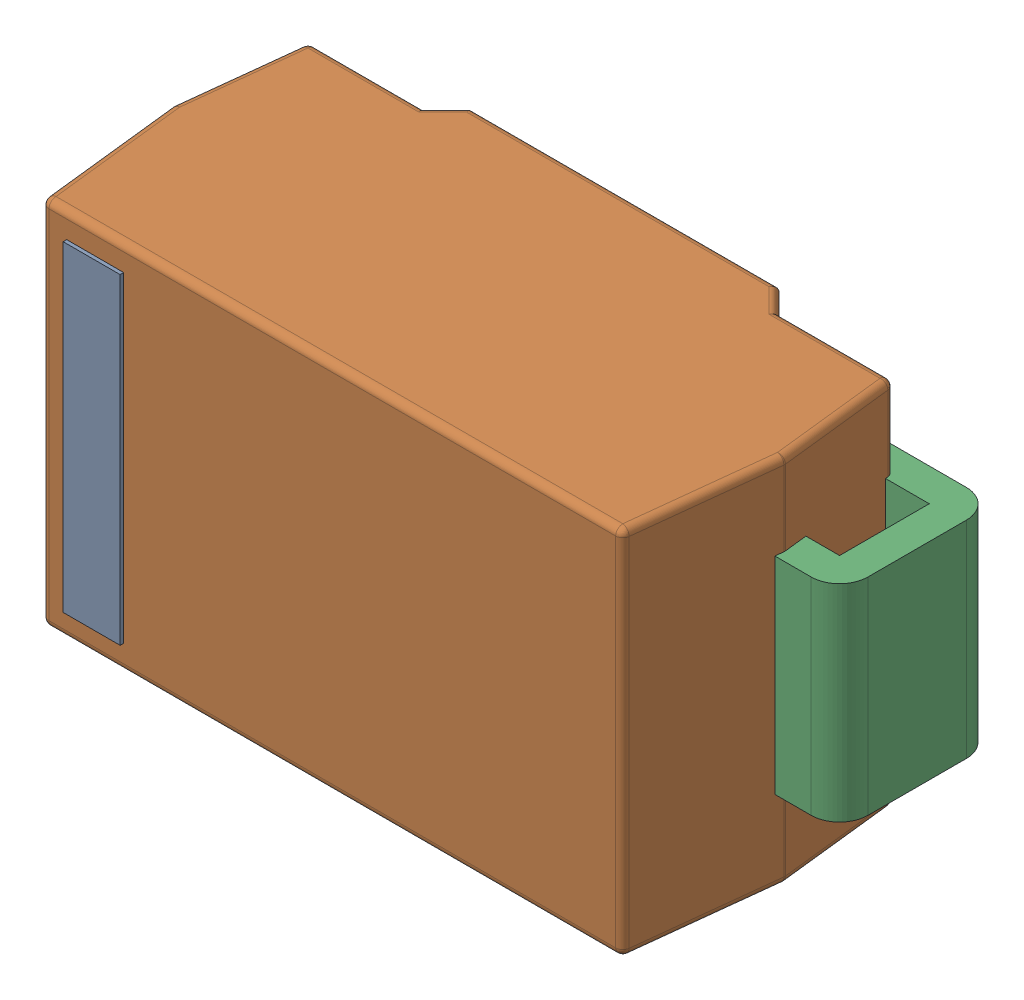
SolidWorks assembly SMA-DIODE, configuration Standard. Lengths in mm.
Overall size (5.2 2.6 2.08).
5 component instances, 4 part files, 0 mates.
Components (placement in the parent):
- SMA-DIODE_1-1: SMA-DIODE_1 [Standard] at origin size (5.2 2.6 2.08)
  - Refdes-1: Refdes [Standard] at (0 0 -3.425) size (0.4 2.25 0.02)
  - Body-1: Body [Standard] at (0 0 -3.425) size (4.3 2.6 2.06)
  - Cathode-1: Cathode [Standard] at (0 0 -3.3) size (1.14 1.45 1.09)
  - Anode-1: Anode [Standard] at (0 0 -3.3) size (1.14 1.45 1.09)
